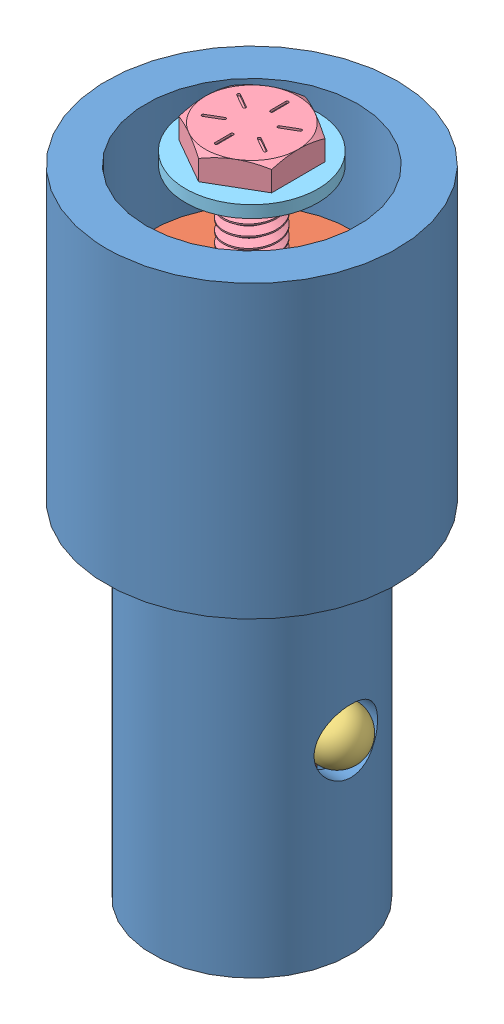
SolidWorks assembly Thesis2_assy, configuration Default. Lengths in mm.
Overall size (34.92 80.57 34.93).
6 component instances, 5 part files, 11 mates.
Components (placement in the parent):
- Thesis2_housing-1: Thesis2_housing [Default] at (16.5285 68.7578 58.7233) size (34.92 76.2 34.92)
- Thesis2_plunger-1: Thesis2_plunger [Default] at (16.5285 21.1328 58.7233) x (-0.405061 0 -0.91429) z (0.91429 0 -0.405061) size (23.81 63.5 23.81)
- ball_bearing_.25-1: ball_bearing_.25 [Default] at (6.2674 43.3578 58.7233) x (0.357494 -0.850065 -0.386766) z (0.526349 -0.158704 0.835326) size (6.35 6.35 6.35)
- ball_bearing_.25-2: ball_bearing_.25 [Default] at (26.7897 43.3578 58.7233) x (0.504321 0.762457 0.405363) z (-0.344855 0.608209 -0.714952) size (6.35 6.35 6.35)
- 92620A540_HIGH-STRENGTH GRADE 8 STEEL CAP SCREW-4: 92620A540_HIGH-STRENGTH GRADE 8 STEEL CAP SCREW [92620A540] at (16.5285 89.9906 58.7233) x (0 -1 0) z (0.503418 0 0.864043) size (23.88 12.83 11.11)
- 92141A029_TYPE 18-8 STAINLESS STEEL FLAT WASHER-1: 92141A029_TYPE 18-8 STAINLESS STEEL FLAT WASHER [92141A029] at (16.5285 97.3328 58.7233) x (0.839362 0 -0.543572) z (0.543572 0 0.839362) size (15.88 1.45 15.88)
Mates (geometry in assembly coordinates):
- Concentric3: concentric: cylinder of Thesis2_housing-1 through (33.991 43.3578 58.7233) axis (-1 0 0) radius 3.81; sphere of ball_bearing_.25-2
- Concentric4: concentric: cylinder of Thesis2_housing-1 through (-0.934 43.3578 58.7233) axis (1 0 0) radius 3.81; sphere of ball_bearing_.25-1
- Tangent9: tangent: sphere of ball_bearing_.25-2; cone of Thesis2_plunger-1 through (16.5285 41.1725 58.7233) axis (0 -1 0)
- Tangent10: tangent: sphere of ball_bearing_.25-1; cone of Thesis2_plunger-1 through (16.5285 41.1725 58.7233) axis (0 -1 0)
- Parallel3: parallel: plane of Thesis2_plunger-1 through (16.5285 21.1328 58.7233) normal (0 -1 0); plane of 92620A540_HIGH-STRENGTH GRADE 8 STEEL CAP SCREW-4 through (22.0974 97.3328 61.9092) normal (0 -1 0)
- Concentric7: concentric: cylinder of Thesis2_plunger-1 through (16.5285 65.5828 58.7233) axis (0 1 0) radius 2.3813; line of 92620A540_HIGH-STRENGTH GRADE 8 STEEL CAP SCREW-4 through (16.5285 89.9906 58.7233) axis (0 -1 0)
- Distance1: distance = 0 mm: plane of 92620A540_HIGH-STRENGTH GRADE 8 STEEL CAP SCREW-4 through (22.0974 97.3328 61.9092) normal (0 -1 0); plane of 92141A029_TYPE 18-8 STAINLESS STEEL FLAT WASHER-1 through (16.5285 97.3328 58.7233) normal (0 -1 0)
- Distance3: distance = 0 mm: plane of 92141A029_TYPE 18-8 STAINLESS STEEL FLAT WASHER-1 through (16.5285 97.3328 58.7233) normal (0 -1 0); plane of Thesis2_housing-1 through (16.5285 97.3328 58.7233) normal (0 1 0)
- Concentric8: concentric: cylinder of 92141A029_TYPE 18-8 STAINLESS STEEL FLAT WASHER-1 through (16.5285 97.3328 58.7233) axis (0 1 0) radius 3.5687; cylinder of Thesis2_housing-1 through (16.5285 97.3328 58.7233) axis (0 -1 0) radius 12.7
- Concentric9: concentric: cylinder of Thesis2_housing-1 through (16.5285 97.3328 58.7233) axis (0 -1 0) radius 12.7; cylinder of Thesis2_plunger-1 through (16.5285 84.6328 58.7233) axis (0 -1 0) radius 11.9062
- Distance4: distance = 0 mm: plane of Thesis2_plunger-1 through (16.5285 68.7578 58.7233) normal (0 -1 0); plane of Thesis2_housing-1 through (16.5285 68.7578 58.7233) normal (0 1 0)
